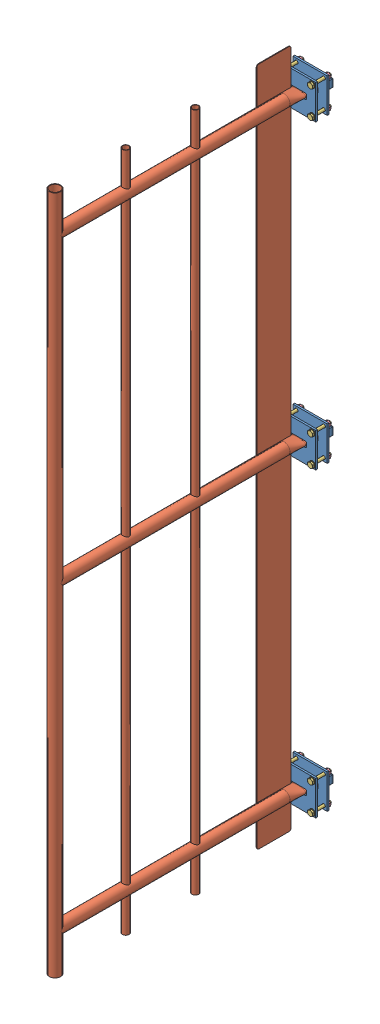
SolidWorks assembly 0410-RAILING ASSEMBLAGE, configuration Predeterminado. Lengths in mm.
Overall size (150 2980 1229).
28 component instances, 4 part files, 19 mates.
Components (placement in the parent):
- 0425-RAILING SUPPORT-1: 0425-RAILING SUPPORT [Predeterminado<Como mecanizada>] at (-16.3127 9.7896 -21) size (150 150 137)
- 0424-LONG RAILING-1: 0424-LONG RAILING [Predeterminado<Como mecanizada>] at (-17.3127 2820.7896 91) x (1 0 0) z (0 -1 0) size (70.2 1225.1 2980)
- M-12x80 DIN-6914-18 and DIN-6916-1: M-12x80 DIN-6914-18 and DIN-6916 [DIN 6914 - M12 x 35 x 21-N] at (43.6873 -50.2104 39) x (0 0 -1) z (1 0 0) size (88 26 26)
- M-12 DIN-6915 and DIN-6916-1: M-12 DIN-6915 and DIN-6916 [Hexagon Nut DIN 6915 - M12 - N] at (43.6873 -50.2104 -31) size (26 26 12)
- M-12x80 DIN-6914-18 and DIN-6916-2: M-12x80 DIN-6914-18 and DIN-6916 [DIN 6914 - M12 x 35 x 21-N] at (43.6873 69.7896 39) x (0 0 -1) z (1 0 0) size (88 26 26)
- M-12x80 DIN-6914-18 and DIN-6916-3: M-12x80 DIN-6914-18 and DIN-6916 [DIN 6914 - M12 x 35 x 21-N] at (-76.3127 69.7896 39) x (0 0 -1) z (1 0 0) size (88 26 26)
- M-12x80 DIN-6914-18 and DIN-6916-4: M-12x80 DIN-6914-18 and DIN-6916 [DIN 6914 - M12 x 35 x 21-N] at (-76.3127 -50.2104 39) x (0 0 -1) z (1 0 0) size (88 26 26)
- M-12 DIN-6915 and DIN-6916-2: M-12 DIN-6915 and DIN-6916 [Hexagon Nut DIN 6915 - M12 - N] at (43.6873 69.7896 -31) size (26 26 12)
- M-12 DIN-6915 and DIN-6916-3: M-12 DIN-6915 and DIN-6916 [Hexagon Nut DIN 6915 - M12 - N] at (-76.3127 69.7896 -31) size (26 26 12)
- M-12 DIN-6915 and DIN-6916-4: M-12 DIN-6915 and DIN-6916 [Hexagon Nut DIN 6915 - M12 - N] at (-76.3127 -50.2104 -31) size (26 26 12)
- 0425-RAILING SUPPORT-2: 0425-RAILING SUPPORT [Predeterminado<Como mecanizada>] at (-16.3127 1330.7896 -21) size (150 150 137)
- 0425-RAILING SUPPORT-3: 0425-RAILING SUPPORT [Predeterminado<Como mecanizada>] at (-16.3127 2651.7896 -21) size (150 150 137)
- M-12 DIN-6915 and DIN-6916-5: M-12 DIN-6915 and DIN-6916 [Hexagon Nut DIN 6915 - M12 - N] at (43.6873 1390.7896 -31) size (26 26 12)
- M-12 DIN-6915 and DIN-6916-6: M-12 DIN-6915 and DIN-6916 [Hexagon Nut DIN 6915 - M12 - N] at (43.6873 2711.7896 -31) size (26 26 12)
- M-12x80 DIN-6914-18 and DIN-6916-5: M-12x80 DIN-6914-18 and DIN-6916 [DIN 6914 - M12 x 35 x 21-N] at (43.6873 1390.7896 39) x (0 0 -1) z (1 0 0) size (88 26 26)
- M-12x80 DIN-6914-18 and DIN-6916-6: M-12x80 DIN-6914-18 and DIN-6916 [DIN 6914 - M12 x 35 x 21-N] at (43.6873 2711.7896 39) x (0 0 -1) z (1 0 0) size (88 26 26)
- M-12 DIN-6915 and DIN-6916-7: M-12 DIN-6915 and DIN-6916 [Hexagon Nut DIN 6915 - M12 - N] at (43.6873 1270.7896 -31) size (26 26 12)
- M-12 DIN-6915 and DIN-6916-8: M-12 DIN-6915 and DIN-6916 [Hexagon Nut DIN 6915 - M12 - N] at (43.6873 2591.7896 -31) size (26 26 12)
- M-12x80 DIN-6914-18 and DIN-6916-7: M-12x80 DIN-6914-18 and DIN-6916 [DIN 6914 - M12 x 35 x 21-N] at (43.6873 1270.7896 39) x (0 0 -1) z (1 0 0) size (88 26 26)
- M-12x80 DIN-6914-18 and DIN-6916-8: M-12x80 DIN-6914-18 and DIN-6916 [DIN 6914 - M12 x 35 x 21-N] at (43.6873 2591.7896 39) x (0 0 -1) z (1 0 0) size (88 26 26)
- M-12x80 DIN-6914-18 and DIN-6916-9: M-12x80 DIN-6914-18 and DIN-6916 [DIN 6914 - M12 x 35 x 21-N] at (-76.3127 1270.7896 39) x (0 0 -1) z (1 0 0) size (88 26 26)
- M-12x80 DIN-6914-18 and DIN-6916-10: M-12x80 DIN-6914-18 and DIN-6916 [DIN 6914 - M12 x 35 x 21-N] at (-76.3127 2591.7896 39) x (0 0 -1) z (1 0 0) size (88 26 26)
- M-12 DIN-6915 and DIN-6916-9: M-12 DIN-6915 and DIN-6916 [Hexagon Nut DIN 6915 - M12 - N] at (-76.3127 1270.7896 -31) size (26 26 12)
- M-12 DIN-6915 and DIN-6916-10: M-12 DIN-6915 and DIN-6916 [Hexagon Nut DIN 6915 - M12 - N] at (-76.3127 2591.7896 -31) size (26 26 12)
- M-12 DIN-6915 and DIN-6916-11: M-12 DIN-6915 and DIN-6916 [Hexagon Nut DIN 6915 - M12 - N] at (-76.3127 1390.7896 -31) size (26 26 12)
- M-12 DIN-6915 and DIN-6916-12: M-12 DIN-6915 and DIN-6916 [Hexagon Nut DIN 6915 - M12 - N] at (-76.3127 2711.7896 -31) size (26 26 12)
- M-12x80 DIN-6914-18 and DIN-6916-11: M-12x80 DIN-6914-18 and DIN-6916 [DIN 6914 - M12 x 35 x 21-N] at (-76.3127 1390.7896 39) x (0 0 -1) z (1 0 0) size (88 26 26)
- M-12x80 DIN-6914-18 and DIN-6916-12: M-12x80 DIN-6914-18 and DIN-6916 [DIN 6914 - M12 x 35 x 21-N] at (-76.3127 2711.7896 39) x (0 0 -1) z (1 0 0) size (88 26 26)
Mates (geometry in assembly coordinates):
- Distancia2: distance = 46 mm aligned: plane of 0424-LONG RAILING-1 through (-45.3127 -159.2104 36) normal (-1 0 0); plane of 0425-RAILING SUPPORT-1 through (-91.3127 -65.2104 21) normal (-1 0 0)
- Distancia3: distance = 94 mm aligned: plane of 0424-LONG RAILING-1 through (-45.3127 -159.2104 186) normal (0 -1 0); plane of 0425-RAILING SUPPORT-1 through (58.6873 -65.2104 21) normal (0 -1 0)
- Coincidente4: coincident anti-aligned: plane of 0425-RAILING SUPPORT-1 through (58.6873 84.7896 29) normal (0 0 1); plane of M-12x80 DIN-6914-18 and DIN-6916-1 through (43.6873 -50.2104 29) normal (0 0 -1)
- Concéntrica1: concentric aligned: cylinder of 0425-RAILING SUPPORT-1 through (43.6873 -50.2104 21) axis (0 0 1) radius 7; cylinder of M-12x80 DIN-6914-18 and DIN-6916-1 through (43.6873 -50.2104 39) axis (0 0 1) radius 6
- Coincidente5: coincident anti-aligned: plane of 0425-RAILING SUPPORT-1 through (58.6873 84.7896 -29) normal (0 0 -1); plane of M-12 DIN-6915 and DIN-6916-1 through (43.6873 -50.2104 -29) normal (0 0 1)
- Coincidente6: coincident anti-aligned: plane of 0425-RAILING SUPPORT-1 through (58.6873 84.7896 29) normal (0 0 1); plane of M-12x80 DIN-6914-18 and DIN-6916-2 through (43.6873 69.7896 29) normal (0 0 -1)
- Concéntrica3: concentric aligned: cylinder of 0425-RAILING SUPPORT-1 through (43.6873 69.7896 21) axis (0 0 1) radius 7; cylinder of M-12x80 DIN-6914-18 and DIN-6916-2 through (43.6873 69.7896 39) axis (0 0 1) radius 6
- Coincidente7: coincident anti-aligned: plane of 0425-RAILING SUPPORT-1 through (58.6873 84.7896 29) normal (0 0 1); plane of M-12x80 DIN-6914-18 and DIN-6916-3 through (-76.3127 69.7896 29) normal (0 0 -1)
- Concéntrica4: concentric aligned: cylinder of 0425-RAILING SUPPORT-1 through (-76.3127 69.7896 21) axis (0 0 1) radius 7; cylinder of M-12x80 DIN-6914-18 and DIN-6916-3 through (-76.3127 69.7896 39) axis (0 0 1) radius 6
- Coincidente8: coincident anti-aligned: plane of 0425-RAILING SUPPORT-1 through (58.6873 84.7896 29) normal (0 0 1); plane of M-12x80 DIN-6914-18 and DIN-6916-4 through (-76.3127 -50.2104 29) normal (0 0 -1)
- Concéntrica5: concentric aligned: cylinder of 0425-RAILING SUPPORT-1 through (-76.3127 -50.2104 21) axis (0 0 1) radius 7; cylinder of M-12x80 DIN-6914-18 and DIN-6916-4 through (-76.3127 -50.2104 39) axis (0 0 1) radius 6
- Concéntrica6: concentric aligned: cylinder of M-12x80 DIN-6914-18 and DIN-6916-1 through (43.6873 -50.2104 39) axis (0 0 1) radius 6; cylinder of M-12 DIN-6915 and DIN-6916-1 through (43.6873 -50.2104 -41) axis (0 0 1) radius 5.1
- Coincidente9: coincident anti-aligned: plane of 0425-RAILING SUPPORT-1 through (58.6873 84.7896 -29) normal (0 0 -1); plane of M-12 DIN-6915 and DIN-6916-2 through (43.6873 69.7896 -29) normal (0 0 1)
- Concéntrica7: concentric aligned: cylinder of M-12x80 DIN-6914-18 and DIN-6916-2 through (43.6873 69.7896 39) axis (0 0 1) radius 6; cylinder of M-12 DIN-6915 and DIN-6916-2 through (43.6873 69.7896 -41) axis (0 0 1) radius 5.1
- Coincidente10: coincident anti-aligned: plane of 0425-RAILING SUPPORT-1 through (58.6873 84.7896 -29) normal (0 0 -1); plane of M-12 DIN-6915 and DIN-6916-3 through (-76.3127 69.7896 -29) normal (0 0 1)
- Concéntrica8: concentric aligned: cylinder of M-12x80 DIN-6914-18 and DIN-6916-3 through (-76.3127 69.7896 39) axis (0 0 1) radius 6; cylinder of M-12 DIN-6915 and DIN-6916-3 through (-76.3127 69.7896 -41) axis (0 0 1) radius 5.1
- Coincidente11: coincident anti-aligned: plane of 0425-RAILING SUPPORT-1 through (58.6873 84.7896 -29) normal (0 0 -1); plane of M-12 DIN-6915 and DIN-6916-4 through (-76.3127 -50.2104 -29) normal (0 0 1)
- Concéntrica9: concentric aligned: cylinder of M-12x80 DIN-6914-18 and DIN-6916-4 through (-76.3127 -50.2104 39) axis (0 0 1) radius 6; cylinder of M-12 DIN-6915 and DIN-6916-4 through (-76.3127 -50.2104 -41) axis (0 0 1) radius 5.1
- Coincidente12: coincident anti-aligned: plane of 0425-RAILING SUPPORT-1 through (-55.3127 -6.7104 -104) normal (0 0 1); plane of 0424-LONG RAILING-1 through (-17.3127 9.7896 -104) normal (0 0 -1)
